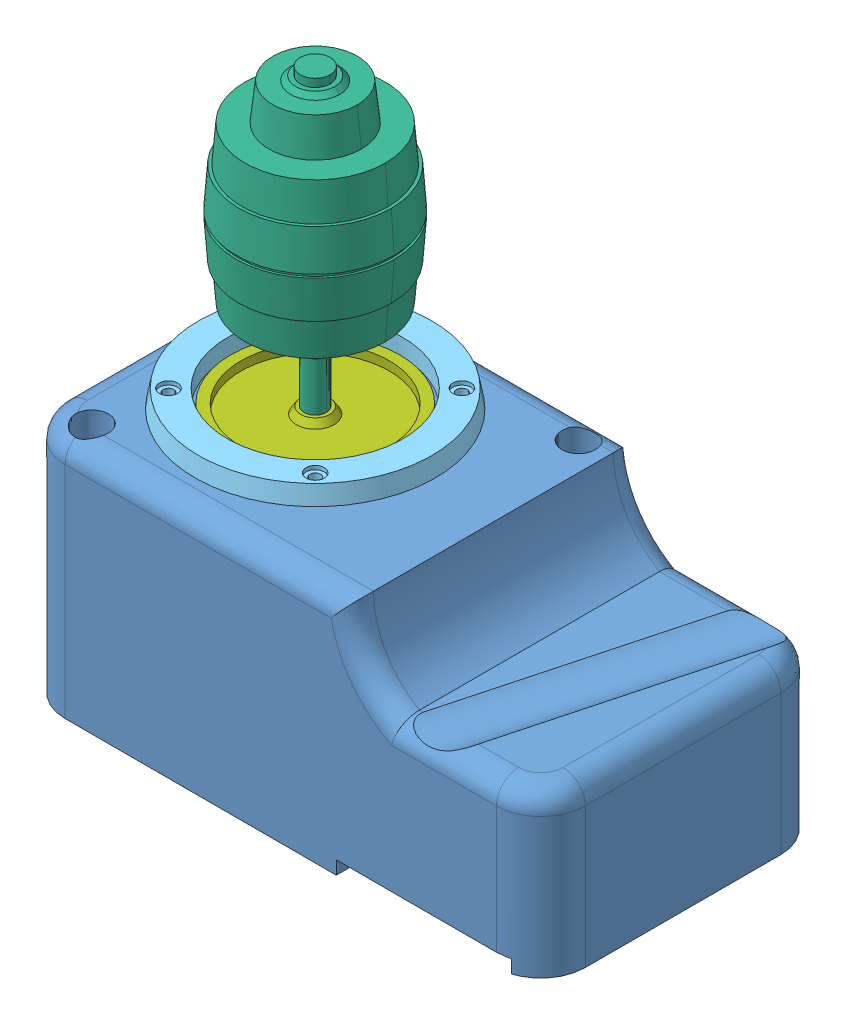
SolidWorks assembly Joystick control v2, configuration Default. Lengths in mm.
Overall size (121.93 122.25 76.37).
90 component instances, 26 part files, 15 mates.
Components (placement in the parent):
- Controller box v2-1: Controller box v2 [Default] at (39.947 30.9265 77.8506) size (117 54.5 64)
- remote_pcb.step-2: remote_pcb.step [Default] at (-86.003 33.9265 172.4506) x (0 0 -1) z (0 1 0) size (47.38 49.95 11.94)
  - PinHeader_1x04_P2.54mm_Vertical.step-1: PinHeader_1x04_P2.54mm_Vertical.step [Default] at (114.8 -120.23 1.63) x (-1 0 0) z (0 0 1) size (2.54 10.16 11.54)
    - SOLID.step-1: SOLID.step [Default] at origin size (2.54 10.16 11.54)
  - R_0402_1005Metric.step-1: R_0402_1005Metric.step [Default] at (89.4 -92.15 1.63) x (0 -1 0) z (0 0 1) size (1 0.5 0.35)
    - SOLID-0.step-1: SOLID-0.step [Default] at origin size (1 0.5 0.35)
  - JST_PH_S3B-PH-K_1x03_P2.00mm_Horizontal.step-1: JST_PH_S3B-PH-K_1x03_P2.00mm_Horizontal.step [Default] at (83.25 -107.15 1.63) x (0 -1 0) z (0 0 1) size (7.9 7.6 8.25)
    - SOLID-1.step-1: SOLID-1.step [Default] at origin size (7.9 7.6 8.25)
  - PinHeader_1x03_P2.54mm_Vertical.step-1: PinHeader_1x03_P2.54mm_Vertical.step [Default] at (92 -90.025 1.63) size (2.54 7.62 11.54)
    - SOLID-2.step-1: SOLID-2.step [Default] at origin size (2.54 7.62 11.54)
  - C_0402_1005Metric.step-1: C_0402_1005Metric.step [Default] at (105.05 -110.05 1.63) x (-1 0 0) z (0 0 1) size (1 0.5 0.5)
    - SOLID-3.step-1: SOLID-3.step [Default] at origin size (1 0.5 0.5)
  - R_0402_1005Metric.step-2: R_0402_1005Metric.step [Default] at (112.1 -90.4 1.63) x (0 1 0) z (0 0 1) size (1 0.5 0.35)
    - SOLID-0.step-1: SOLID-0.step [Default] at origin size (1 0.5 0.35)
  - PinHeader_1x04_P2.54mm_Vertical.step-2: PinHeader_1x04_P2.54mm_Vertical.step [Default] at (120.65 -120.28 1.63) x (-1 0 0) z (0 0 1) size (2.54 10.16 11.54)
    - SOLID.step-1: SOLID.step [Default] at origin size (2.54 10.16 11.54)
  - PinHeader_1x08_P2.54mm_Vertical.step-1: PinHeader_1x08_P2.54mm_Vertical.step [Default] at (105.275 -79.85 1.63) x (0 -1 0) z (0 0 1) size (2.54 20.32 11.54)
    - SOLID-4.step-1: SOLID-4.step [Default] at origin size (2.54 20.32 11.54)
  - L_1206_3216Metric.step-1: L_1206_3216Metric.step [Default] at (88.65 -97.75 1.63) x (0 1 0) z (0 0 1) size (3.2 1.6 1.6)
    - SOLID-5.step-1: SOLID-5.step [Default] at origin size (3.2 1.6 1.6)
  - R_0402_1005Metric.step-3: R_0402_1005Metric.step [Default] at (111.31 -107.5 1.63) x (0 -1 0) z (0 0 1) size (1 0.5 0.35)
    - SOLID-0.step-1: SOLID-0.step [Default] at origin size (1 0.5 0.35)
  - R_0402_1005Metric.step-4: R_0402_1005Metric.step [Default] at (90.81 -120.505 1.63) size (1 0.5 0.35)
    - SOLID-0.step-1: SOLID-0.step [Default] at origin size (1 0.5 0.35)
  - SW_CuK_JS202011AQN_DPDT_Angled.step-1: SW_CuK_JS202011AQN_DPDT_Angled.step [Default] at (118.175 -91.2005 1.63) x (0 1 0) z (0 0 1) size (9 5.6 6.5)
    - SOLID-6.step-1: SOLID-6.step [Default] at origin size (9 5.6 6.5)
  - SOT-23-6.step-1: SOT-23-6.step [Default] at (110.5 -86.85 1.63) size (2.8 2.9 1.55)
    - SOLID-7.step-1: SOLID-7.step [Default] at origin size (2.8 2.9 1.55)
  - C_1210_3225Metric.step-1: C_1210_3225Metric.step [Default] at (114.85 -89.35 1.63) x (0 -1 0) z (0 0 1) size (3.2 2.5 2.5)
    - SOLID-8.step-1: SOLID-8.step [Default] at origin size (3.2 2.5 2.5)
  - PinHeader_1x08_P2.54mm_Vertical.step-2: PinHeader_1x08_P2.54mm_Vertical.step [Default] at (96.02 -125.75 1.63) x (0 1 0) z (0 0 1) size (2.54 20.32 11.54)
    - SOLID-4.step-1: SOLID-4.step [Default] at origin size (2.54 20.32 11.54)
  - C_0402_1005Metric.step-2: C_0402_1005Metric.step [Default] at (90.2 -105.5 1.63) x (-1 0 0) z (0 0 1) size (1 0.5 0.5)
    - SOLID-3.step-1: SOLID-3.step [Default] at origin size (1 0.5 0.5)
  - C_0402_1005Metric.step-3: C_0402_1005Metric.step [Default] at (94.9 -105.2 1.63) x (0 -1 0) z (0 0 1) size (1 0.5 0.5)
    - SOLID-3.step-1: SOLID-3.step [Default] at origin size (1 0.5 0.5)
  - Crystal_SMD_3225-4Pin_3.2x2.5mm.step-1: Crystal_SMD_3225-4Pin_3.2x2.5mm.step [Default] at (92.2 -102.75 1.63) x (0 1 0) z (0 0 1) size (3.2 2.5 0.64)
    - SOLID-9.step-1: SOLID-9.step [Default] at origin size (3.2 2.5 0.64)
  - JST_PH_S2B-PH-K_1x02_P2.00mm_Horizontal.step-1: JST_PH_S2B-PH-K_1x02_P2.00mm_Horizontal.step [Default] at (83.3 -117.6 1.63) x (0 -1 0) z (0 0 1) size (5.9 7.6 8.25)
    - SOLID-10.step-1: SOLID-10.step [Default] at origin size (5.9 7.6 8.25)
  - L_Coilcraft_XAL5020-XXX.step-1: L_Coilcraft_XAL5020-XXX.step [Default] at (112.75 -81.2 1.63) x (-1 0 0) z (0 0 1) size (5.48 5.68 2)
    - COMPOUND.step-1: COMPOUND.step [Default] at origin size (5.48 5.68 2)
  - C_0402_1005Metric.step-4: C_0402_1005Metric.step [Default] at (107.5 -101.25 1.63) x (0 -1 0) z (0 0 1) size (1 0.5 0.5)
    - SOLID-3.step-1: SOLID-3.step [Default] at origin size (1 0.5 0.5)
  - LQFP-48_7x7mm_P0.5mm.step-1: LQFP-48_7x7mm_P0.5mm.step [Default] at (101.25 -104.25 1.63) size (9 9 1.5)
    - SOLID-11.step-1: SOLID-11.step [Default] at origin size (9 9 1.5)
  - R_0402_1005Metric.step-5: R_0402_1005Metric.step [Default] at (111.85 -104.2 1.63) x (0 -1 0) z (0 0 1) size (1 0.5 0.35)
    - SOLID-0.step-1: SOLID-0.step [Default] at origin size (1 0.5 0.35)
  - R_0402_1005Metric.step-6: R_0402_1005Metric.step [Default] at (111.31 -102 1.63) x (0 1 0) z (0 0 1) size (1 0.5 0.35)
    - SOLID-0.step-1: SOLID-0.step [Default] at origin size (1 0.5 0.35)
  - C_0402_1005Metric.step-5: C_0402_1005Metric.step [Default] at (93.6 -107.15 1.63) x (0 1 0) z (0 0 1) size (1 0.5 0.5)
    - SOLID-3.step-1: SOLID-3.step [Default] at origin size (1 0.5 0.5)
  - C_0402_1005Metric.step-6: C_0402_1005Metric.step [Default] at (96.25 -100.25 1.63) x (-1 0 0) z (0 0 1) size (1 0.5 0.5)
    - SOLID-3.step-1: SOLID-3.step [Default] at origin size (1 0.5 0.5)
  - C_0402_1005Metric.step-7: C_0402_1005Metric.step [Default] at (91.5 -99.75 1.63) size (1 0.5 0.5)
    - SOLID-3.step-1: SOLID-3.step [Default] at origin size (1 0.5 0.5)
  - JST_PH_S3B-PH-K_1x03_P2.00mm_Horizontal.step-2: JST_PH_S3B-PH-K_1x03_P2.00mm_Horizontal.step [Default] at (83.25 -96.65 1.63) x (0 -1 0) z (0 0 1) size (7.9 7.6 8.25)
    - SOLID-1.step-1: SOLID-1.step [Default] at origin size (7.9 7.6 8.25)
  - C_0402_1005Metric.step-8: C_0402_1005Metric.step [Default] at (89.7 -101.75 1.63) x (0 -1 0) z (0 0 1) size (1 0.5 0.5)
    - SOLID-3.step-1: SOLID-3.step [Default] at origin size (1 0.5 0.5)
  - JST_PH_S3B-PH-K_1x03_P2.00mm_Horizontal.step-3: JST_PH_S3B-PH-K_1x03_P2.00mm_Horizontal.step [Default] at (83.25 -86.4 1.63) x (0 -1 0) z (0 0 1) size (7.9 7.6 8.25)
    - SOLID-1.step-1: SOLID-1.step [Default] at origin size (7.9 7.6 8.25)
  - PinHeader_1x03_P2.54mm_Vertical.step-2: PinHeader_1x03_P2.54mm_Vertical.step [Default] at (91.45 -125.7 1.63) x (0 -1 0) z (0 0 1) size (2.54 7.62 11.54)
    - SOLID-2.step-1: SOLID-2.step [Default] at origin size (2.54 7.62 11.54)
  - C_0805_2012Metric.step-1: C_0805_2012Metric.step [Default] at (95 -98.5 1.63) x (-1 0 0) z (0 0 1) size (2 1.25 1.25)
    - SOLID-12.step-1: SOLID-12.step [Default] at origin size (2 1.25 1.25)
  - R_0402_1005Metric.step-7: R_0402_1005Metric.step [Default] at (110.35 -90.4 1.63) x (0 -1 0) z (0 0 1) size (1 0.5 0.35)
    - SOLID-0.step-1: SOLID-0.step [Default] at origin size (1 0.5 0.35)
  - LED_0603_1608Metric.step-1: LED_0603_1608Metric.step [Default] at (88.65 -121.45 1.63) x (0 -1 0) z (0 0 1) size (1.6 0.8 1.1)
    - SOLID-13.step-1: SOLID-13.step [Default] at origin size (1.6 0.8 1.1)
  - PinHeader_1x02_P2.54mm_Vertical.step-1: PinHeader_1x02_P2.54mm_Vertical.step [Default] at (120.65 -97 1.63) x (0 -1 0) z (0 0 1) size (2.54 5.08 11.54)
    - SOLID-14.step-1: SOLID-14.step [Default] at origin size (2.54 5.08 11.54)
  - SOT-223.step-1: SOT-223.step [Default] at (99.05 -91.9 1.63) x (-1 0 0) z (0 0 1) size (7 6.5 1.7)
    - SOLID-15.step-1: SOLID-15.step [Default] at origin size (7 6.5 1.7)
  - SW_Tactile_SPST_NO_Straight_CK_PTS636Sx25SMTRLFS.step-1: SW_Tactile_SPST_NO_Straight_CK_PTS636Sx25SMTRLFS.step [Default] at (89.5 -114.35 1.63) x (0 1 0) z (0 0 1) size (8 3.7 2.55)
    - COMPOUND-16.step-1: COMPOUND-16.step [Default] at origin size (8 3.7 2.55)
  - C_0402_1005Metric.step-9: C_0402_1005Metric.step [Default] at (98.25 -98.25 1.63) size (1 0.5 0.5)
    - SOLID-3.step-1: SOLID-3.step [Default] at origin size (1 0.5 0.5)
  - R_0402_1005Metric.step-8: R_0402_1005Metric.step [Default] at (108.6 -90.4 1.63) x (0 1 0) z (0 0 1) size (1 0.5 0.35)
    - SOLID-0.step-1: SOLID-0.step [Default] at origin size (1 0.5 0.35)
  - C_0402_1005Metric.step-10: C_0402_1005Metric.step [Default] at (92.2 -107.15 1.63) x (0 1 0) z (0 0 1) size (1 0.5 0.5)
    - SOLID-3.step-1: SOLID-3.step [Default] at origin size (1 0.5 0.5)
  - D_SOD-123.step-1: D_SOD-123.step [Default] at (106.55 -87.55 1.63) x (0 1 0) z (0 0 1) size (3.8 1.6 1.25)
    - SOLID-17.step-1: SOLID-17.step [Default] at origin size (3.8 1.6 1.25)
  - remote_pcb PCB.step-1: remote_pcb PCB.step [Default] at origin size (46.45 49.95 1.58)
- D400B-M4-10KB 3-Axis Joystick with Button.STEP-1: D400B-M4-10KB 3-Axis Joystick with Button.STEP [Default] at (14.6974 52.6765 76.8503) size (76.37 95.5 76.37)
  - Mount Ring^D400B-M4-10KB 3-Axis Joystick with Button.STEP-1: Mount Ring^D400B-M4-10KB 3-Axis Joystick with Button.STEP [Default] at (0 28.75 0) x (0.707107 0 0.707107) z (-0.707107 0 0.707107) size (54 4 54)
  - Main^D400B-M4-10KB 3-Axis Joystick with Button.STEP-1: Main^D400B-M4-10KB 3-Axis Joystick with Button.STEP [Default] at origin size (59.55 95.5 49.55)
  - Seal^D400B-M4-10KB 3-Axis Joystick with Button.STEP-1: Seal^D400B-M4-10KB 3-Axis Joystick with Button.STEP [Default] at (0 25.75 0) x (0.707107 0 0.707107) z (-0.707107 0 0.707107) size (48.47 4 48.47)
- cr123_holder v3.step-1: cr123_holder v3.step [Default] at (71.947 46.8265 63.8506) x (0 1 0) z (0 0 1) size (18.65 21.86 45.5)
Mates (geometry in assembly coordinates):
- Coincident2: coincident anti-aligned: plane of Controller box v2-1 through (88.447 50.7865 55.8506) normal (0 -1 0); plane of AABattery Holder.stp-1 through (87.197 50.7865 104.1606) normal (0 1 0)
- Coincident3: coincident anti-aligned: line of Controller box v2-1 through (88.447 36.4265 47.8506) axis (0 -1 0); line of AABattery Holder.stp-1 through (88.447 41.7865 47.8506) axis (0 1 0)
- Parallel1: parallel anti-aligned: plane of Controller box v2-1 through (88.447 80.4265 47.8506) normal (0 0 1); plane of AABattery Holder.stp-1 through (58.197 49.7865 47.8506) normal (0 0 -1)
- Concentric1: concentric aligned: circle of Controller box v2-1; circle of D400B-M4-10KB 3-Axis Joystick with Button.STEP-1/Mount Ring^D400B-M4-10KB 3-Axis Joystick with Button.STEP-1
- Concentric2: concentric aligned: circle of Controller box v2-1; circle of D400B-M4-10KB 3-Axis Joystick with Button.STEP-1/Mount Ring^D400B-M4-10KB 3-Axis Joystick with Button.STEP-1
- Coincident6: coincident anti-aligned: plane of Controller box v2-1 through (-8.553 78.4265 99.8506) normal (0 -1 0); plane of D400B-M4-10KB 3-Axis Joystick with Button.STEP-1/Main^D400B-M4-10KB 3-Axis Joystick with Button.STEP-1 through (14.6974 78.4265 76.8503) normal (0 1 0)
- Concentric3: concentric aligned: circle of Controller box v2-1; circle of remote_pcb.step-2/remote_pcb PCB.step-1
- Concentric5: concentric aligned: circle of Controller box v2-1; circle of remote_pcb.step-2/remote_pcb PCB.step-1
- Coincident8: coincident anti-aligned: plane of Controller box v2-1 through (39.197 33.9265 52.3506) normal (0 1 0); plane of remote_pcb.step-2/remote_pcb PCB.step-1 through (16.822 33.9265 72.9756) normal (0 -1 0)
- Symmetric1: symmetric: plane of Controller box v2-1 through (52.447 25.9265 45.8506) normal (1 0 0); plane of Controller box v2-1 through (91.447 25.9265 50.8506) normal (-1 0 0); plane of ? through (71.947 -18.1565 62.8506) normal (-1 0 0)
- Distance1: distance = 7.8 mm: plane of cr123_holder.step-1 through (62.247 49.1865 99.0506) normal (0 0 1); plane of Controller box v2-1 through (52.447 25.9265 50.8506) normal (0 0 -1)
- Coincident10: coincident anti-aligned: plane of Controller box v2-1 through (88.447 50.7865 55.8506) normal (0 -1 0); plane of cr123_holder.step-1 through (71.947 50.7865 76.3506) normal (0 1 0)
- Symmetric2: symmetric aligned: plane of Controller box v2-1 through (52.447 25.9265 109.8506) normal (1 0 0); plane of Controller box v2-1 through (91.447 25.9265 47.8506) normal (-1 0 0); plane of cr123_holder v3.step-1 through (71.947 46.8265 63.8506) normal (-1 0 0)
- Distance2: distance = 7.8 mm anti-aligned: plane of cr123_holder v3.step-1 through (61.047 46.8265 100.0506) normal (0 0 1); plane of Controller box v2-1 through (88.447 80.4265 107.8506) normal (0 0 -1)
- Coincident11: coincident anti-aligned: plane of Controller box v2-1 through (88.447 48.4265 55.8506) normal (0 -1 0); plane of cr123_holder v3.step-1 through (71.947 48.4265 77.3506) normal (0 1 0)
